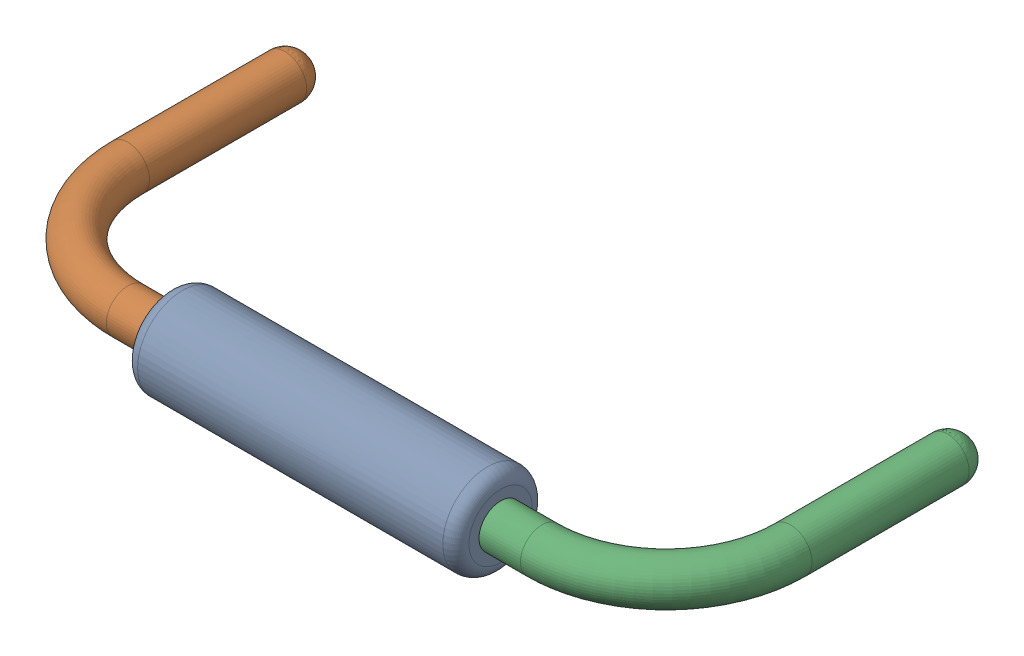
SolidWorks assembly R2, configuration Défaut. Lengths in mm.
Overall size (10.82 1.37 5.33).
4 component instances, 3 part files, 0 mates.
Components (placement in the parent):
- Open CASCADE STEP translator 6.8 1.10.1-1: Open CASCADE STEP translator 6.8 1.10.1 [Défaut] at origin size (10.82 1.37 5.33)
  - Body_1_7-1: Body_1_7 [Défaut] at origin size (5.08 1.37 1.37)
  - Pin_1_4-1: Pin_1_4 [Défaut] at origin size (3.2 0.66 4.98)
  - Pin_2_4-1: Pin_2_4 [Défaut] at (20.32 0 0) x (-1 0 0) z (0 0 1) size (3.2 0.66 4.98)
